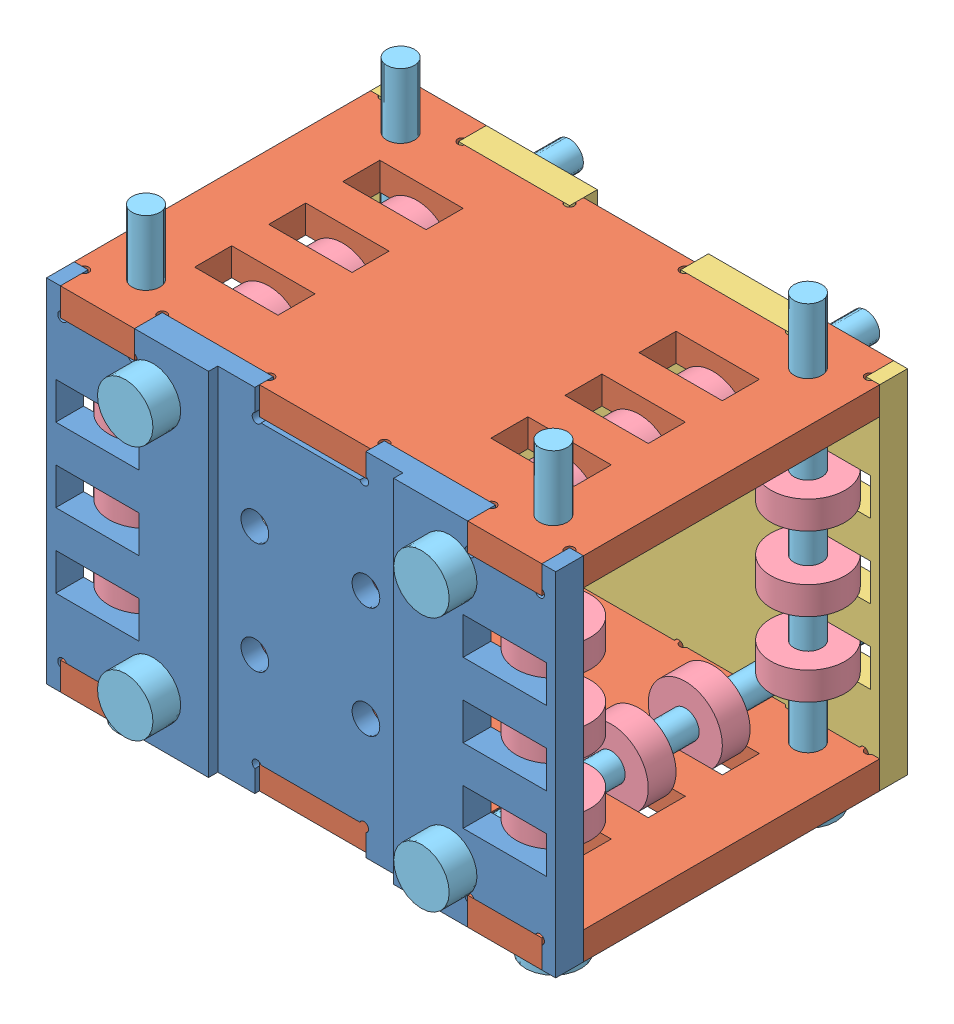
SolidWorks assembly 滑套, configuration 默认. Lengths in mm.
Overall size (55.06 48 48).
36 component instances, 5 part files, 25 mates.
Components (placement in the parent):
- 铝管滑套-1: 铝管滑套 [默认] at (-5.1085 -1.419 48.5) size (55 38 3)
- 滑套板B-1: 滑套板B [默认] at (-5.1085 -17.419 32.5) x (0 0 1) z (0 -1 0) size (38 55 3)
- 铝管滑套对面-1: 铝管滑套对面 [默认] at (-5.1085 -1.419 13.5) size (55 38 3) (hidden)
- 滑套板B-2: 滑套板B [默认] at (-5.1085 17.581 32.5) x (0 0 1) z (0 -1 0) size (38 55 3)
- 3-8-3轴承-1: 3-8-3轴承 [默认] at (-21.1085 -15.169 40.5) x (-0.839993 0.542597 0) z (0 0 1) size (8 8 3)
- 3-45螺栓-1: 3-45螺栓 [默认] at (-21.1085 -15.169 51.5) x (0.877969 0.478717 0) z (0 0 -1) size (6 6 48)
- 3-8-3轴承-2: 3-8-3轴承 [默认] at (-21.1085 -15.169 32.5) x (-0.839993 0.542597 0) z (0 0 1) size (8 8 3)
- 3-8-3轴承-3: 3-8-3轴承 [默认] at (-21.1085 -15.169 24.5) x (-0.839993 0.542597 0) z (0 0 1) size (8 8 3)
- 3-45螺栓-2: 3-45螺栓 [默认] at (-27.1085 -20.419 46.25) x (0.680808 0 -0.732462) z (0 1 0) size (6 6 48)
- 3-8-3轴承-4: 3-8-3轴承 [默认] at (-27.1085 -9.419 46.25) x (-0.839993 0 -0.542597) z (0 1 0) size (8 8 3)
- 3-8-3轴承-5: 3-8-3轴承 [默认] at (-27.1085 -1.419 46.25) x (-0.839993 0 -0.542597) z (0 1 0) size (8 8 3)
- 3-8-3轴承-6: 3-8-3轴承 [默认] at (-27.1085 6.581 46.25) x (-0.839993 0 -0.542597) z (0 1 0) size (8 8 3)
- 3-8-3轴承-7: 3-8-3轴承 [默认] at (-27.1085 6.581 18.75) x (-0.839993 0 -0.542597) z (0 1 0) size (8 8 3)
- 3-8-3轴承-8: 3-8-3轴承 [默认] at (16.8915 6.581 46.25) x (-0.839993 0 -0.542597) z (0 1 0) size (8 8 3)
- 3-8-3轴承-9: 3-8-3轴承 [默认] at (16.8915 6.581 18.75) x (-0.839993 0 -0.542597) z (0 1 0) size (8 8 3)
- 3-8-3轴承-10: 3-8-3轴承 [默认] at (-27.1085 -1.419 18.75) x (-0.839993 0 -0.542597) z (0 1 0) size (8 8 3)
- 3-8-3轴承-11: 3-8-3轴承 [默认] at (16.8915 -1.419 46.25) x (-0.839993 0 -0.542597) z (0 1 0) size (8 8 3)
- 3-8-3轴承-12: 3-8-3轴承 [默认] at (16.8915 -1.419 18.75) x (-0.839993 0 -0.542597) z (0 1 0) size (8 8 3)
- 3-8-3轴承-13: 3-8-3轴承 [默认] at (-27.1085 -9.419 18.75) x (-0.839993 0 -0.542597) z (0 1 0) size (8 8 3)
- 3-8-3轴承-14: 3-8-3轴承 [默认] at (16.8915 -9.419 46.25) x (-0.839993 0 -0.542597) z (0 1 0) size (8 8 3)
- 3-8-3轴承-15: 3-8-3轴承 [默认] at (16.8915 -9.419 18.75) x (-0.839993 0 -0.542597) z (0 1 0) size (8 8 3)
- 3-45螺栓-3: 3-45螺栓 [默认] at (-27.1085 -20.419 18.75) x (0.680808 0 -0.732462) z (0 1 0) size (6 6 48)
- 3-45螺栓-4: 3-45螺栓 [默认] at (16.8915 -20.419 46.25) x (0.680808 0 -0.732462) z (0 1 0) size (6 6 48)
- 3-45螺栓-5: 3-45螺栓 [默认] at (16.8915 -20.419 18.75) x (0.680808 0 -0.732462) z (0 1 0) size (6 6 48)
- 3-45螺栓-6: 3-45螺栓 [默认] at (-21.1085 12.331 51.5) x (0.877969 0.478717 0) z (0 0 -1) size (6 6 48)
- 3-45螺栓-7: 3-45螺栓 [默认] at (10.8915 -15.169 51.5) x (0.877969 0.478717 0) z (0 0 -1) size (6 6 48)
- 3-45螺栓-8: 3-45螺栓 [默认] at (10.8915 12.331 51.5) x (0.877969 0.478717 0) z (0 0 -1) size (6 6 48)
- 3-8-3轴承-16: 3-8-3轴承 [默认] at (-21.1085 12.331 24.5) x (-0.839993 0.542597 0) z (0 0 1) size (8 8 3)
- 3-8-3轴承-17: 3-8-3轴承 [默认] at (10.8915 -15.169 24.5) x (-0.839993 0.542597 0) z (0 0 1) size (8 8 3)
- 3-8-3轴承-18: 3-8-3轴承 [默认] at (10.8915 12.331 24.5) x (-0.839993 0.542597 0) z (0 0 1) size (8 8 3)
- 3-8-3轴承-19: 3-8-3轴承 [默认] at (-21.1085 12.331 32.5) x (-0.839993 0.542597 0) z (0 0 1) size (8 8 3)
- 3-8-3轴承-20: 3-8-3轴承 [默认] at (10.8915 -15.169 32.5) x (-0.839993 0.542597 0) z (0 0 1) size (8 8 3)
- 3-8-3轴承-21: 3-8-3轴承 [默认] at (10.8915 12.331 32.5) x (-0.839993 0.542597 0) z (0 0 1) size (8 8 3)
- 3-8-3轴承-22: 3-8-3轴承 [默认] at (-21.1085 12.331 40.5) x (-0.839993 0.542597 0) z (0 0 1) size (8 8 3)
- 3-8-3轴承-23: 3-8-3轴承 [默认] at (10.8915 -15.169 40.5) x (-0.839993 0.542597 0) z (0 0 1) size (8 8 3)
- 3-8-3轴承-24: 3-8-3轴承 [默认] at (10.8915 12.331 40.5) x (-0.839993 0.542597 0) z (0 0 1) size (8 8 3)
Mates (geometry in assembly coordinates):
- 重合1: coincident: plane of assembly; plane of assembly; plane of 铝管滑套-1 through (-23.1085 -17.419 21.5) normal (0 -1 0); plane of 滑套板B-1 through (-5.1085 -17.419 32.5) normal (0 1 0)
- 重合2: coincident: plane of assembly; plane of assembly; plane of 铝管滑套-1 through (-5.1085 -1.419 51.5) normal (0 0 1); plane of 滑套板B-1 through (-32.6085 -20.419 51.5) normal (0 0 1)
- 重合3: coincident: plane of assembly; plane of assembly; plane of 铝管滑套-1 through (-31.1085 -20.419 21.5) normal (1 0 0); plane of 滑套板B-1 through (-31.1085 -17.419 32.5) normal (-1 0 0)
- 重合4: coincident: plane of assembly; plane of 滑套板B-1 through (-5.1085 -17.419 16.5) normal (0 0 -1); plane of 铝管滑套对面-1 through (-5.1085 -1.419 16.5) normal (0 0 1)
- 重合5: coincident: plane of assembly; plane of assembly; plane of 滑套板B-1 through (-32.6085 -20.419 13.5) normal (-1 0 0); plane of 铝管滑套对面-1 through (-32.6085 17.581 16.5) normal (-1 0 0)
- 重合6: coincident: plane of assembly; plane of assembly; plane of 滑套板B-1 through (-5.1085 -17.419 32.5) normal (0 1 0); plane of 铝管滑套对面-1 through (-23.1085 -17.419 -13.5) normal (0 -1 0)
- 重合7: coincident: plane of assembly; plane of assembly; plane of 铝管滑套-1 through (-23.1085 14.581 21.5) normal (0 1 0); plane of 滑套板B-2 through (-5.1085 14.581 32.5) normal (0 -1 0)
- 重合8: coincident: plane of assembly; plane of assembly; plane of 铝管滑套-1 through (-5.1085 -1.419 51.5) normal (0 0 1); plane of 滑套板B-2 through (-32.6085 14.581 51.5) normal (0 0 1)
- 重合9: coincident: plane of assembly; plane of assembly; plane of 铝管滑套-1 through (-32.6085 17.581 51.5) normal (-1 0 0); plane of 滑套板B-2 through (-32.6085 14.581 13.5) normal (-1 0 0)
- 距离1: distance = 0.5 mm: plane of assembly; plane of assembly; plane of 3-8-3轴承-1 through (-21.1085 -15.169 42) normal (0 0 1); plane of 滑套板B-1 through (-25.6085 -10.419 42.5) normal (0 0 -1)
- 同心1: concentric: cylinder of assembly; cylinder of assembly; cylinder of 铝管滑套-1 through (-21.1085 -15.169 21.5) axis (0 0 1) radius 1.5; cylinder of 3-8-3轴承-1 through (-21.1085 -15.169 39) axis (0 0 1) radius 1.5
- 同心2: concentric: cylinder of assembly; cylinder of assembly; cylinder of 铝管滑套-1 through (-21.1085 -15.169 21.5) axis (0 0 1) radius 1.5; cylinder of 3-45螺栓-1 through (-21.1085 -15.169 6.5) axis (0 0 1) radius 1.5
- 重合11: coincident: plane of assembly; plane of assembly; plane of 铝管滑套-1 through (-5.1085 -1.419 51.5) normal (0 0 1); plane of 3-45螺栓-1 through (-21.1085 -15.169 51.5) normal (0 0 -1)
- 同心3: concentric: cylinder of assembly; cylinder of assembly; cylinder of 3-45螺栓-1 through (-21.1085 -15.169 6.5) axis (0 0 1) radius 1.5; cylinder of 3-8-3轴承-2 through (-21.1085 -15.169 31) axis (0 0 1) radius 4
- 距离2: distance = 0.5 mm: plane of assembly; plane of assembly; plane of 3-8-3轴承-2 through (-21.1085 -15.169 34) normal (0 0 1); plane of 滑套板B-1 through (-25.6085 -10.419 34.5) normal (0 0 -1)
- 同心4: concentric: cylinder of assembly; cylinder of assembly; cylinder of 3-45螺栓-1 through (-21.1085 -15.169 6.5) axis (0 0 1) radius 1.5; cylinder of 3-8-3轴承-3 through (-21.1085 -15.169 23) axis (0 0 1) radius 4
- 距离3: distance = 0.5 mm: plane of assembly; plane of assembly; plane of 滑套板B-1 through (-25.6085 -10.419 26.5) normal (0 0 -1); plane of 3-8-3轴承-3 through (-21.1085 -15.169 26) normal (0 0 1)
- 同心5: concentric: cylinder of assembly; cylinder of assembly; cylinder of 滑套板B-1 through (-27.1085 -17.419 46.25) axis (0 -1 0) radius 1.5; cylinder of 3-45螺栓-2 through (-27.1085 24.581 46.25) axis (0 -1 0) radius 1.5
- 重合14: coincident: plane of assembly; plane of assembly; plane of 滑套板B-1 through (-5.1085 -20.419 32.5) normal (0 -1 0); plane of 3-45螺栓-2 through (-27.1085 -20.419 46.25) normal (0 1 0)
- 同心6: concentric: cylinder of assembly; cylinder of assembly; cylinder of 3-45螺栓-2 through (-27.1085 24.581 46.25) axis (0 -1 0) radius 1.5; cylinder of 3-8-3轴承-4 through (-27.1085 -10.919 46.25) axis (0 1 0) radius 4
- 距离4: distance = 0.5 mm: plane of assembly; plane of assembly; plane of 3-8-3轴承-4 through (-27.1085 -10.919 46.25) normal (0 -1 0); plane of 铝管滑套-1 through (-31.6085 -11.419 41.5) normal (0 1 0)
- 同心7: concentric: cylinder of assembly; cylinder of assembly; cylinder of 3-45螺栓-2 through (-27.1085 24.581 46.25) axis (0 -1 0) radius 1.5; cylinder of 3-8-3轴承-5 through (-27.1085 -2.919 46.25) axis (0 1 0) radius 4
- 同心8: concentric: cylinder of assembly; cylinder of assembly; cylinder of 3-45螺栓-2 through (-27.1085 24.581 46.25) axis (0 -1 0) radius 1.5; cylinder of 3-8-3轴承-6 through (-27.1085 5.081 46.25) axis (0 1 0) radius 4
- 距离5: distance = 0.5 mm: plane of assembly; plane of assembly; plane of 3-8-3轴承-5 through (-27.1085 -2.919 46.25) normal (0 -1 0); plane of 铝管滑套-1 through (-31.6085 -3.419 41.5) normal (0 1 0)
- 距离6: distance = 0.5 mm: plane of assembly; plane of assembly; plane of 铝管滑套-1 through (-31.6085 4.581 41.5) normal (0 1 0); plane of 3-8-3轴承-6 through (-27.1085 5.081 46.25) normal (0 -1 0)
